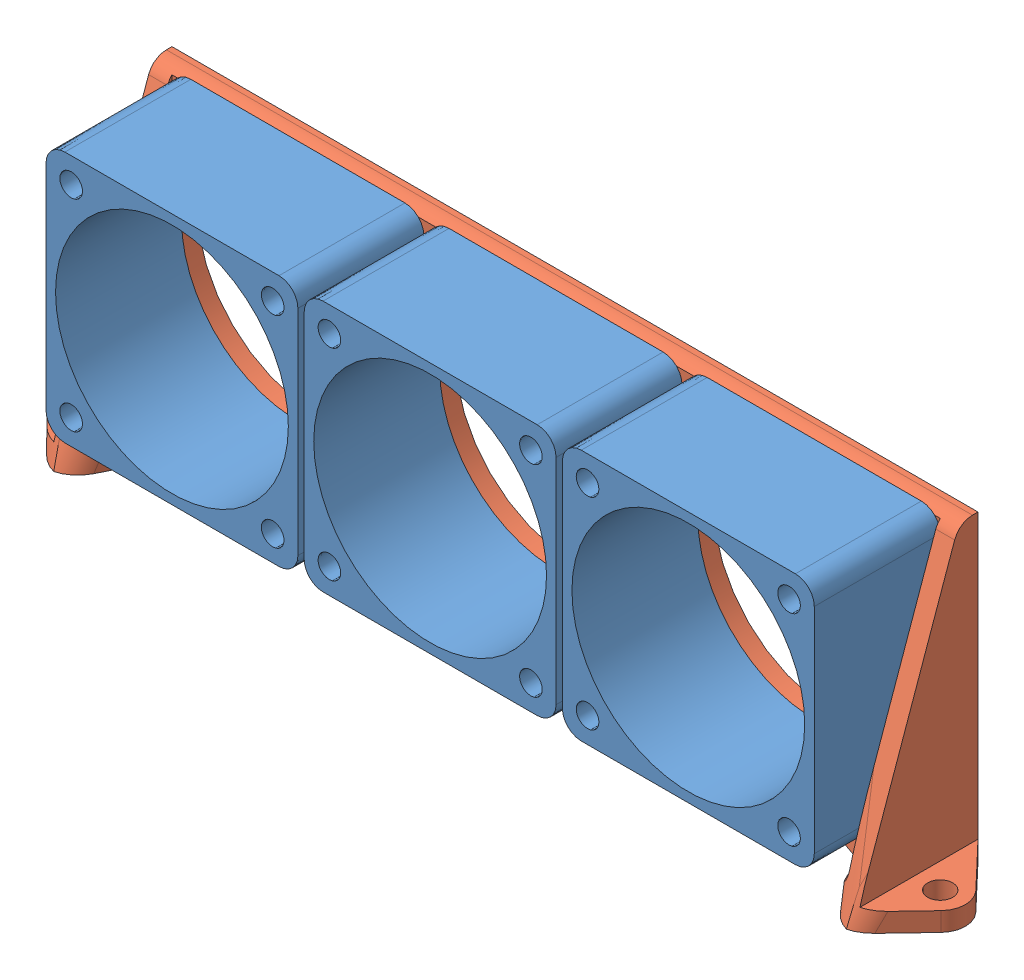
SolidWorks assembly controller, configuration Default. Lengths in mm.
Overall size (144 48 23).
4 component instances, 2 part files, 9 mates.
Components (placement in the parent):
- fan-1: fan [Default] at (-10.5854 30.8525 27.3889) size (40 40 20)
- fan-2: fan [Default] at (30.4146 30.8525 27.3889) size (40 40 20)
- fan-3: fan [Default] at (71.4146 30.8525 27.3889) size (40 40 20)
- fan_plate-1: fan_plate [Default] at (30.4146 30.8525 24.3889) size (144 48 19.83)
Mates (geometry in assembly coordinates):
- Coincident1: coincident aligned: plane of fan-1 through (-30.5854 50.8525 47.3889) normal (0 1 0); plane of fan-2 through (10.4146 50.8525 47.3889) normal (0 1 0)
- Coincident2: coincident aligned: plane of fan-1 through (-30.5854 50.8525 47.3889) normal (0 1 0); plane of fan-3 through (51.4146 50.8525 47.3889) normal (0 1 0)
- Coincident3: coincident aligned: plane of fan-3 through (71.4146 30.8525 47.3889) normal (0 0 1); plane of fan-1 through (-10.5854 30.8525 47.3889) normal (0 0 1)
- Coincident4: coincident aligned: plane of fan-3 through (71.4146 30.8525 47.3889) normal (0 0 1); plane of fan-2 through (30.4146 30.8525 47.3889) normal (0 0 1)
- Distance1: distance = 1 mm anti-aligned: plane of fan-3 through (51.4146 10.8525 47.3889) normal (-1 0 0); plane of fan-2 through (50.4146 10.8525 47.3889) normal (1 0 0)
- Distance2: distance = 1 mm anti-aligned: plane of fan-2 through (10.4146 10.8525 47.3889) normal (-1 0 0); plane of fan-1 through (9.4146 10.8525 47.3889) normal (1 0 0)
- Coincident6: coincident aligned: plane of fan-1 through (-30.5854 50.8525 47.3889) normal (0 1 0); plane of fan_plate-1 through (-30.5854 50.8525 27.3889) normal (0 1 0)
- Coincident7: coincident: plane of fan-3 through (91.4146 10.8525 47.3889) normal (1 0 0); plane of fan_plate-1 through (91.4146 10.8525 27.3889) normal (1 0 0)
- Coincident8: coincident anti-aligned: plane of fan-2 through (30.4146 30.8525 27.3889) normal (0 0 -1); plane of fan_plate-1 through (30.4146 30.8525 27.3889) normal (0 0 1)
